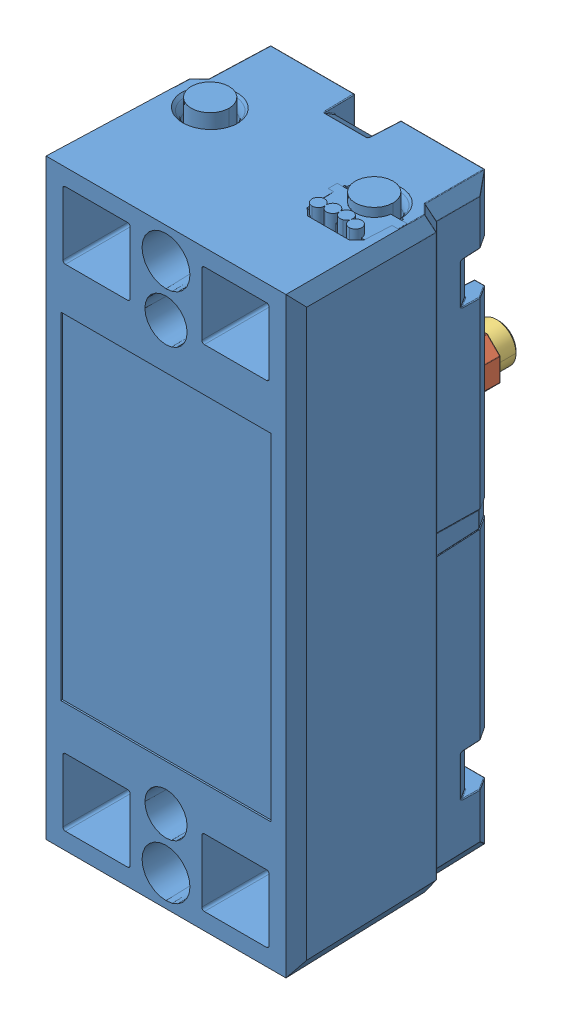
SolidWorks assembly Talon SRX (217-8080), configuration Default. Lengths in mm.
Overall size (30.47 71.42 30.05).
5 component instances, 3 part files, 0 mates.
Components (placement in the parent):
- Talon SRX (217-8080).step-1: Talon SRX (217-8080).step [Default] at origin size (30.47 491.79 30.05)
  - 217-8080-baseRev4.step-1: 217-8080-baseRev4.step [Default] at origin size (30.47 491.79 25.2)
  - 217-8080-002 Rev1.step-1: 217-8080-002 Rev1.step [Default] at (0 13.05 -9.65) x (1 0 0) z (0 -1 0) size (25.15 2.9 7.5)
  - 217-8080-005 Rev1_91251A105.step-1: 217-8080-005 Rev1_91251A105.step [Default] at (-9.525 13.05 -5.8875) size (4.65 4.65 7.61)
  - 217-8080-005 Rev1_91251A105.step-2: 217-8080-005 Rev1_91251A105.step [Default] at (9.525 13.05 -5.8875) size (4.65 4.65 7.61)
